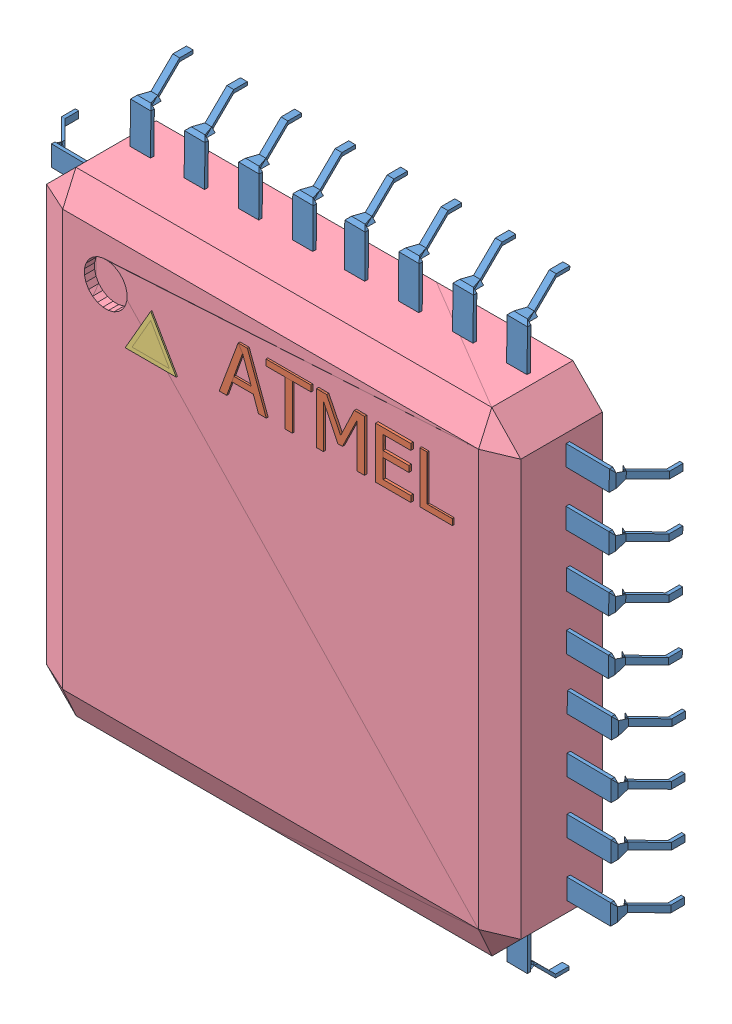
SolidWorks assembly QFP80P900X900X120-32N, configuration Default. Lengths in mm.
Overall size (9.13 9.12 1.66).
37 component instances, 5 part files, 0 mates.
Components (placement in the parent):
- Pin_microcontoller-1: Pin_microcontoller [Default] at (-2.8113 -4.0273 -0.452) x (0.999946 -0.010347 0) z (0 0 1) size (0.3 1.03 0.73)
- Pin_microcontoller-2: Pin_microcontoller [Default] at (-2.0034 -4.0303 -0.455) x (0.999946 -0.010347 0) z (0 0 1) size (0.3 1.03 0.73)
- Pin_microcontoller-3: Pin_microcontoller [Default] at (-1.2066 -4.0418 -0.4449) x (0.999946 -0.010347 0) z (0 0 1) size (0.3 1.03 0.73)
- Pin_microcontoller-4: Pin_microcontoller [Default] at (-0.3987 -4.0447 -0.4479) x (0.999946 -0.010347 0) z (0 0 1) size (0.3 1.03 0.73)
- Pin_microcontoller-5: Pin_microcontoller [Default] at (1.9774 -4.0152 -0.4378) x (0.999946 -0.010347 0) z (0 0 1) size (0.3 1.03 0.73)
- Pin_microcontoller-6: Pin_microcontoller [Default] at (0.3728 -4.0007 -0.4449) x (0.999946 -0.010347 0) z (0 0 1) size (0.3 1.03 0.73)
- Pin_microcontoller-7: Pin_microcontoller [Default] at (2.7853 -4.0181 -0.4408) x (0.999946 -0.010347 0) z (0 0 1) size (0.3 1.03 0.73)
- Pin_microcontoller-8: Pin_microcontoller [Default] at (1.1807 -4.0036 -0.4479) x (0.999946 -0.010347 0) z (0 0 1) size (0.3 1.03 0.73)
- Pin_microcontoller-9: Pin_microcontoller [Default] at (1.1678 4.0418 -0.4458) x (-0.999946 0.010347 0) z (0 0 1) size (0.3 1.03 0.73)
- Pin_microcontoller-10: Pin_microcontoller [Default] at (0.3599 4.0447 -0.4489) x (-0.999946 0.010347 0) z (0 0 1) size (0.3 1.03 0.73)
- Pin_microcontoller-11: Pin_microcontoller [Default] at (1.9645 4.0303 -0.4559) x (-0.999946 0.010347 0) z (0 0 1) size (0.3 1.03 0.73)
- Pin_microcontoller-12: Pin_microcontoller [Default] at (-2.0162 4.0152 -0.4388) x (-0.999946 0.010347 0) z (0 0 1) size (0.3 1.03 0.73)
- Pin_microcontoller-13: Pin_microcontoller [Default] at (-0.4116 4.0007 -0.4458) x (-0.999946 0.010347 0) z (0 0 1) size (0.3 1.03 0.73)
- Pin_microcontoller-14: Pin_microcontoller [Default] at (-2.8241 4.0181 -0.4418) x (-0.999946 0.010347 0) z (0 0 1) size (0.3 1.03 0.73)
- Pin_microcontoller-15: Pin_microcontoller [Default] at (-1.2195 4.0036 -0.4489) x (-0.999946 0.010347 0) z (0 0 1) size (0.3 1.03 0.73)
- Pin_microcontoller-16: Pin_microcontoller [Default] at (2.7724 4.0273 -0.4529) x (-0.999946 0.010347 0) z (0 0 1) size (0.3 1.03 0.73)
- Pin_microcontoller-17: Pin_microcontoller [Default] at (-4.0031 -0.3628 -0.4556) x (-0.010347 -0.999946 0) z (0 0 1) size (0.3 1.03 0.73)
- Pin_microcontoller-18: Pin_microcontoller [Default] at (-4.0297 2.8212 -0.4627) x (-0.010347 -0.999946 0) z (0 0 1) size (0.3 1.03 0.73)
- Pin_microcontoller-19: Pin_microcontoller [Default] at (-4.0442 1.2166 -0.4556) x (-0.010347 -0.999946 0) z (0 0 1) size (0.3 1.03 0.73)
- Pin_microcontoller-20: Pin_microcontoller [Default] at (-4.0471 0.4087 -0.4587) x (-0.010347 -0.999946 0) z (0 0 1) size (0.3 1.03 0.73)
- Pin_microcontoller-21: Pin_microcontoller [Default] at (-4.0326 2.0133 -0.4657) x (-0.010347 -0.999946 0) z (0 0 1) size (0.3 1.03 0.73)
- Pin_microcontoller-22: Pin_microcontoller [Default] at (-4.0176 -1.9675 -0.4486) x (-0.010347 -0.999946 0) z (0 0 1) size (0.3 1.03 0.73)
- Pin_microcontoller-23: Pin_microcontoller [Default] at (-4.0205 -2.7754 -0.4516) x (-0.010347 -0.999946 0) z (0 0 1) size (0.3 1.03 0.73)
- Pin_microcontoller-24: Pin_microcontoller [Default] at (-4.006 -1.1707 -0.4587) x (-0.010347 -0.999946 0) z (0 0 1) size (0.3 1.03 0.73)
- Pin_microcontoller-25: Pin_microcontoller [Default] at (4.0326 -1.9751 -0.4479) x (0.010347 0.999946 0) z (0 0 1) size (0.3 1.03 0.73)
- Pin_microcontoller-26: Pin_microcontoller [Default] at (4.0297 -2.783 -0.4449) x (0.010347 0.999946 0) z (0 0 1) size (0.3 1.03 0.73)
- Pin_microcontoller-27: Pin_microcontoller [Default] at (4.0031 0.401 -0.4378) x (0.010347 0.999946 0) z (0 0 1) size (0.3 1.03 0.73)
- Pin_microcontoller-28: Pin_microcontoller [Default] at (4.0442 -1.1784 -0.4378) x (0.010347 0.999946 0) z (0 0 1) size (0.3 1.03 0.73)
- Pin_microcontoller-29: Pin_microcontoller [Default] at (4.0471 -0.3705 -0.4408) x (0.010347 0.999946 0) z (0 0 1) size (0.3 1.03 0.73)
- Pin_microcontoller-30: Pin_microcontoller [Default] at (4.0176 2.0057 -0.4307) x (0.010347 0.999946 0) z (0 0 1) size (0.3 1.03 0.73)
- Pin_microcontoller-31: Pin_microcontoller [Default] at (4.0205 2.8136 -0.4338) x (0.010347 0.999946 0) z (0 0 1) size (0.3 1.03 0.73)
- Pin_microcontoller-32: Pin_microcontoller [Default] at (4.006 1.2089 -0.4408) x (0.010347 0.999946 0) z (0 0 1) size (0.3 1.03 0.73)
- ATMEL-1: ATMEL [Default] at (0.9788 2.3333 0.8105) size (3.47 0.76 0.04)
  - ATMEL-1-1: ATMEL-1 [Default] at origin size (3.47 0.76 0.04)
- ATMEL-2: ATMEL [Default] at (0.9788 2.3333 0.8105) size (3.47 0.76 0.04)
- _-1: _ [Default] at (-1.7862 2.132 0.7865) size (0.76 0.66 0.05)
- QFP80P900X900X120-32N-1: QFP80P900X900X120-32N [Default] at origin size (7.08 7.08 1.6)
